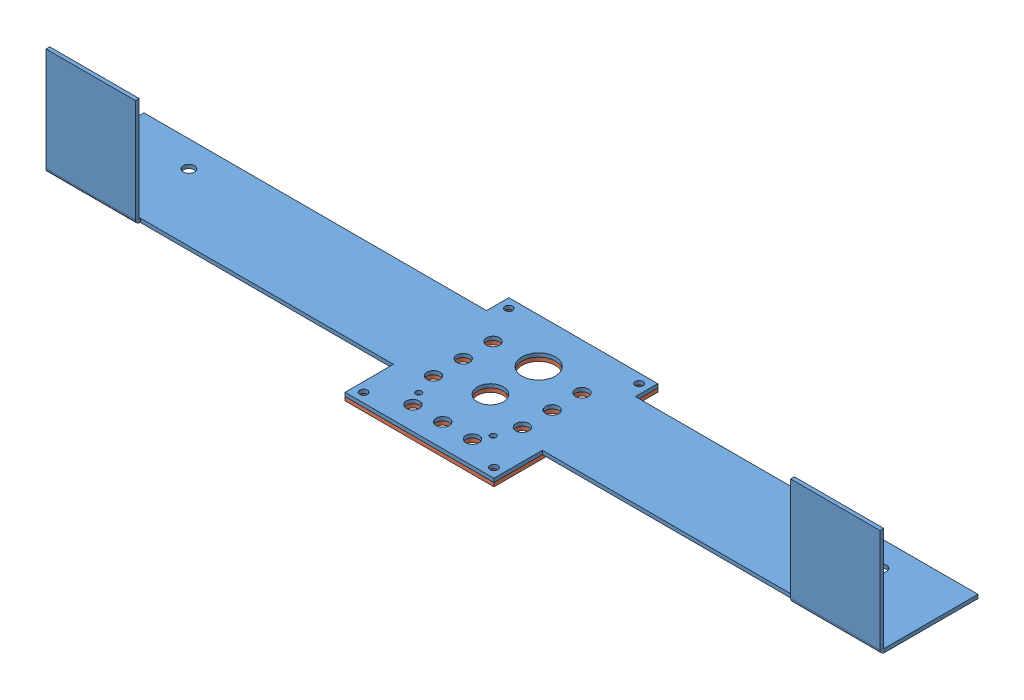
SolidWorks assembly interior wall _ working, configuration Default. Lengths in mm.
Overall size (711.2 95.25 139.7).
2 component instances, 2 part files, 2 mates.
Components (placement in the parent):
- interior wheel well-1: interior wheel well [Default] at (49.5572 487.3333 580.9042) size (711.2 92.08 139.7)
- 3CIM TB Special Shaft Plate-1: 3CIM TB Special Shaft Plate [Default] at (298.8826 479.9858 608.4816) x (1 0 0) z (0 -1 0) size (127 139.7 3.17)
Mates (geometry in assembly coordinates):
- Coincident1: coincident: plane of interior wheel well-1 through (-56.7174 483.1608 589.4316) normal (0 -1 0); plane of 3CIM TB Special Shaft Plate-1 through (362.3826 483.1608 710.0816) normal (0 1 0)
- Coincident3: coincident aligned: circle of interior wheel well-1; circle of 3CIM TB Special Shaft Plate-1
